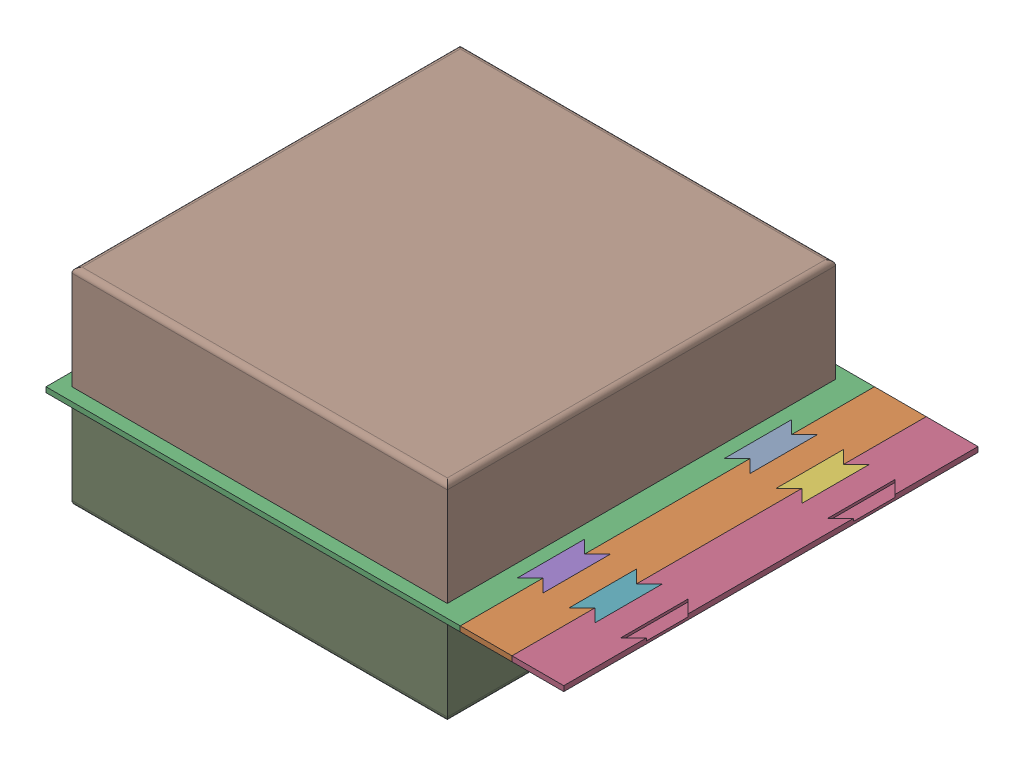
SolidWorks assembly Filter ASSEM, configuration Default. Lengths in mm.
Overall size (254 101.6 203.2).
10 component instances, 5 part files, 18 mates.
Components (placement in the parent):
- Ducktail-1: Ducktail [Default] at (-0.5328 -4.2159 -9.1091) size (12.7 1.27 33.02)
- filter extension-1: filter extension [Default] at (15.9814 -2.9459 42.3301) size (25.4 2.54 203.2)
- NASA Filter-1: NASA Filter [Default] at (-98.3186 -4.2159 42.3301) size (203.2 2.54 203.2)
- filter extension-2: filter extension [Default] at (41.3814 -2.9459 42.3301) size (25.4 2.54 203.2)
- Ducktail-2: Ducktail [Default] at (-0.5328 -4.2159 92.4909) size (12.7 1.27 33.02)
- Ducktail-3: Ducktail [Default] at (24.8672 -4.2159 -9.1091) size (12.7 1.27 33.02)
- Ducktail-4: Ducktail [Default] at (24.8672 -4.2159 92.4909) size (12.7 1.27 33.02)
- nasa patent-1: nasa patent [Default] at (-101.4936 47.8541 42.3301) size (184.15 50.8 196.85)
- nasa patent-2: nasa patent [Default] at (-101.4936 -53.7459 42.3301) x (-1 0 0) z (0 0 1) size (184.15 50.8 196.85)
- filter actual-2: filter actual [Default] at (-176.942 -2.2384 132.5001) size (162.44 25.6 180.34)
Mates (geometry in assembly coordinates):
- Coincident1: coincident aligned: line of filter extension-1 through (3.2814 -2.9459 143.9301) axis (1 0 0); line of NASA Filter-1 through (-199.9186 -2.9459 143.9301) axis (1 0 0)
- Coincident2: coincident anti-aligned: line of filter extension-1 through (3.2814 -2.9459 1.6901) axis (0 0 1); line of NASA Filter-1 through (3.2814 -2.9459 82.9701) axis (0 0 -1)
- Coincident5: coincident aligned: line of Ducktail-1 through (9.6314 -4.2159 8.0401) axis (0 0 -1); line of filter extension-1 through (9.6314 -4.2159 8.0401) axis (0 0 -1)
- Coincident6: coincident: point of Ducktail-1; point of NASA Filter-1
- Coincident8: coincident: point of NASA Filter-1; point of Ducktail-2
- Coincident9: coincident aligned: line of filter extension-1 through (3.2814 -2.9459 143.9301) axis (1 0 0); line of filter extension-2 through (28.6814 -2.9459 143.9301) axis (1 0 0)
- Coincident10: coincident anti-aligned: line of filter extension-1 through (28.6814 -2.9459 143.9301) axis (0 0 -1); line of filter extension-2 through (28.6814 -2.9459 103.2901) axis (0 0 1)
- Coincident11: coincident: point of filter extension-2; point of Ducktail-4
- Coincident12: coincident: point of filter extension-1; point of Ducktail-3
- Coincident15: coincident anti-aligned: line of nasa patent-2 through (-9.4186 -2.9459 137.5801) axis (-1 0 0); line of NASA Filter-1 through (-193.5686 -2.9459 137.5801) axis (1 0 0)
- Coincident17: coincident anti-aligned: line of NASA Filter-1 through (-9.4186 -2.9459 -52.9199) axis (-1 0 0); line of nasa patent-2 through (-193.5686 -2.9459 -52.9199) axis (1 0 0)
- Coincident18: coincident: plane of nasa patent-1 through (-104.3117 -2.9459 42.3301) normal (0 -1 0); plane of nasa patent-2 through (-101.4936 -2.9459 42.3301) normal (0 1 0)
- Coincident19: coincident anti-aligned: plane of NASA Filter-1 through (-193.5686 -2.9459 137.5801) normal (1 0 0); plane of nasa patent-2 through (-193.5686 -2.9459 137.5801) normal (-1 0 0)
- Coincident23: coincident anti-aligned: plane of nasa patent-2 through (-9.4186 -2.9459 132.5001) normal (0 0 -1); plane of filter actual-2 through (-176.942 -2.2384 132.5001) normal (0 0 1)
- Coincident25: coincident aligned: line of nasa patent-2 through (-14.4986 -2.9459 -47.8399) axis (0 0 1); line of filter actual-2 through (-14.4986 -2.9459 -47.8399) axis (0 0 1)
- Coincident26: coincident: plane of nasa patent-1 through (-104.3117 -2.9459 42.3301) normal (0 -1 0); plane of nasa patent-2 through (-101.4936 -2.9459 42.3301) normal (0 1 0)
- Coincident30: coincident: line of NASA Filter-1 through (-9.4186 -2.9459 -52.9199) axis (-1 0 0); line of nasa patent-1 through (-9.4186 -2.9459 -52.9199) axis (-1 0 0)
- Coincident31: coincident anti-aligned: line of NASA Filter-1 through (-9.4186 -2.9459 -52.9199) axis (0 0 1); line of nasa patent-1 through (-9.4186 -2.9459 137.5801) axis (0 0 -1)
